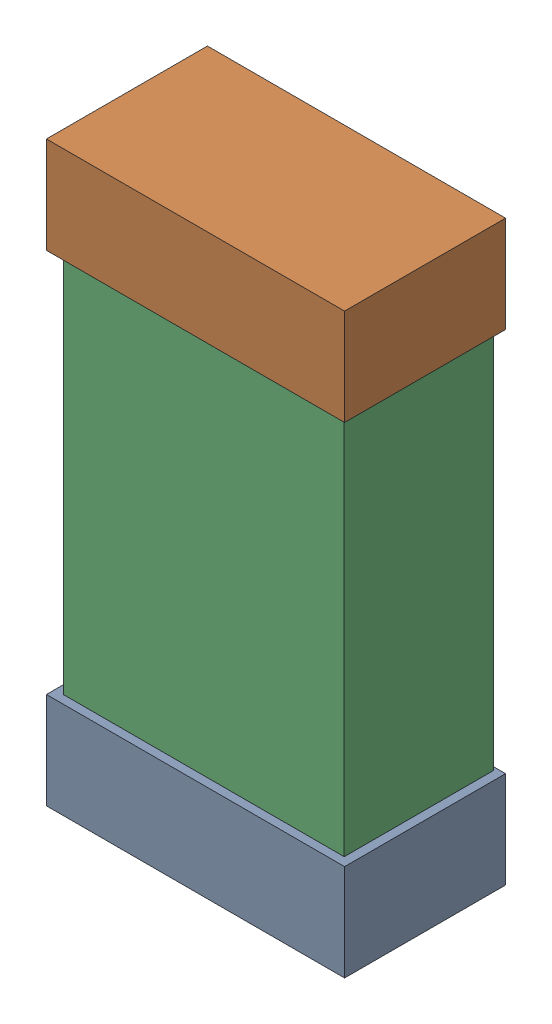
SolidWorks assembly C42, configuration Default. Lengths in mm.
Overall size (0.85 1.65 0.46).
6 component instances, 2 part files, 0 mates.
Components (placement in the parent):
- 432138512_38-1: 432138512_38 [Default] at (12.5499 49.4138 -0.8715) size (0.85 0.28 0.46)
  - Extruded-1: Extruded [Default] at origin size (0.85 0.28 0.46)
- 432138512_39-1: 432138512_39 [Default] at (12.5499 50.7853 -0.8715) size (0.85 0.28 0.46)
  - Extruded-1: Extruded [Default] at origin size (0.85 0.28 0.46)
- 432124816_19-1: 432124816_19 [Default] at (12.5499 50.0995 -0.8615) size (0.8 1.5 0.42)
  - Extruded (1)-1: Extruded (1) [Default] at origin size (0.8 1.5 0.42)
